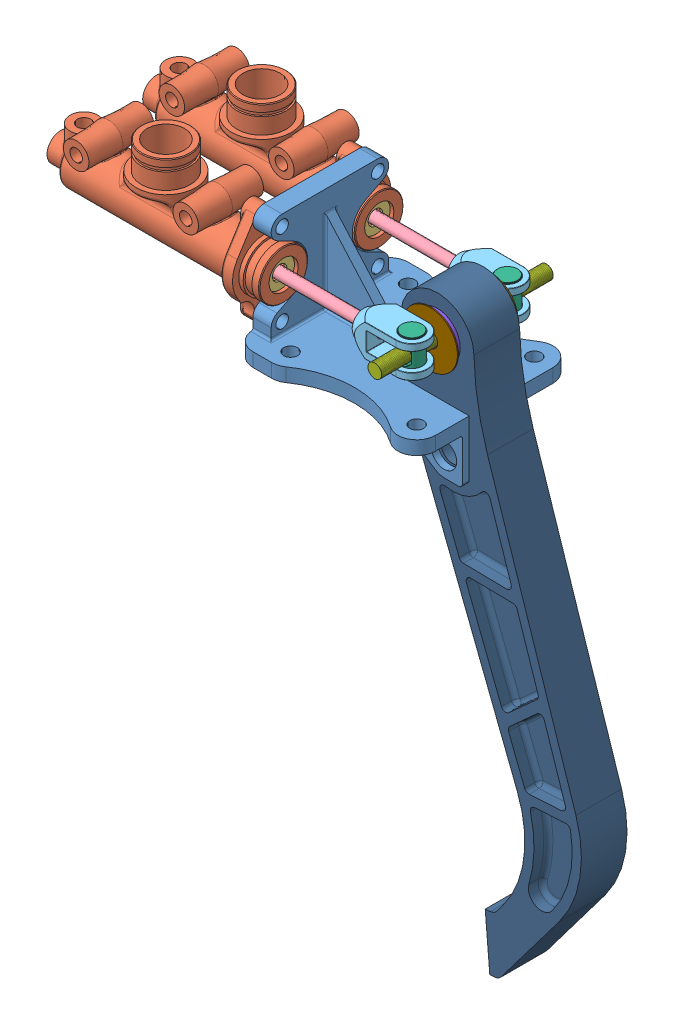
SolidWorks assembly pedalASM, configuration Default. Lengths in mm.
Overall size (389.96 409.12 121.21).
18 component instances, 10 part files, 27 mates.
Components (placement in the parent):
- PedalMastercylMount-1: PedalMastercylMount [Default] at (-61.6568 -16.4521 -5.96) size (127.05 113.66 107.95)
- mastercylinder asm-1: mastercylinder asm [Default] at (-69.6578 12.1229 27.314) x (0 0 -1) z (1 0 0) size (45.21 75.99 223.71)
  - mastercylinder-1: mastercylinder [Default] at origin size (45.21 75.99 154.88)
  - mastercylinder retaining washer-1: mastercylinder retaining washer [Default] at (0 0 17.145) size (20.83 20.83 1.91)
  - mastercylinder pushrod-1: mastercylinder pushrod [Default] at (0 0 90.551) x (-0.12806 0.991766 0) z (0 0 1) size (10.67 10.67 107.24)
- mastercylinder asm-2: mastercylinder asm [Default] at (-69.6578 12.1229 -39.234) x (0 0 -1) z (1 0 0) size (45.21 75.99 223.71)
  - mastercylinder-1: mastercylinder [Default] at origin size (45.21 75.99 154.88)
  - mastercylinder retaining washer-1: mastercylinder retaining washer [Default] at (0 0 17.145) size (20.83 20.83 1.91)
  - mastercylinder pushrod-1: mastercylinder pushrod [Default] at (0 0 90.551) x (-0.12806 0.991766 0) z (0 0 1) size (10.67 10.67 107.24)
- clevis-1: clevis [Default] at (41.4545 0.9469 27.5045) x (0 0 -1) z (1 0 0) size (21.97 22.28 44.25)
- clevis-2: clevis [Default] at (41.4545 0.9469 -39.0435) x (0 0 -1) z (1 0 0) size (21.97 22.28 44.25)
- clevis pin-3: clevis pin [Default] at (41.4545 0.2865 -39.0435) size (14.27 23.6 14.27)
- clevis pin-4: clevis pin [Default] at (41.4545 0.2865 27.5045) size (14.27 23.6 14.27)
- Balance bar-2: Balance bar [Default] at (41.5999 12.1359 -6.2775) x (-0.943579 -0.331147 0) z (-0.331147 0.943579 0) size (20.15 121.21 20.15)
- Bushing-1: Bushing [Default] at (41.6783 12.1634 14.2965) x (0 0 -1) z (0.852085 -0.523404 0) size (40.64 31.75 31.75)
- Washer-1: Washer [Default] at (41.6783 12.1634 15.0585) x (0 0 -1) z (0.988589 -0.150638 0) size (0.76 38.1 38.1)
- Washer-2: Washer [Default] at (41.6783 12.1634 -26.3435) x (0 0 -1) z (0.984471 -0.175545 0) size (0.76 38.1 38.1)
- brakepedaltest1-1: brakepedaltest1 [Default] at (52.6432 -51.3771 -5.96) x (0 0 1) z (-0.940935 -0.338587 0) size (31.75 384.44 115.48)
Mates (geometry in assembly coordinates):
- Coincident1: coincident anti-aligned: plane of PedalMastercylMount-1 through (-61.6568 12.1229 27.314) normal (-1 0 0); plane of mastercylinder asm-1/mastercylinder-1 through (-61.6568 40.6979 27.314) normal (1 0 0)
- Concentric1: concentric aligned: cylinder of PedalMastercylMount-1 through (-48.9568 40.6979 27.314) axis (-1 0 0) radius 4.3656; cylinder of mastercylinder asm-1/mastercylinder-1 through (-61.6568 40.6979 27.314) axis (-1 0 0) radius 4.3656
- Concentric2: concentric aligned: cylinder of PedalMastercylMount-1 through (-48.9568 -16.4521 27.314) axis (-1 0 0) radius 4.3656; cylinder of mastercylinder asm-1/mastercylinder-1 through (-61.6568 -16.4521 27.314) axis (-1 0 0) radius 4.3656
- Coincident2: coincident anti-aligned: plane of PedalMastercylMount-1 through (-61.6568 12.1229 27.314) normal (-1 0 0); plane of mastercylinder asm-2/mastercylinder-1 through (-61.6568 40.6979 -39.234) normal (1 0 0)
- Concentric3: concentric aligned: cylinder of PedalMastercylMount-1 through (-48.9568 40.6979 -39.234) axis (-1 0 0) radius 4.3656; cylinder of mastercylinder asm-2/mastercylinder-1 through (-61.6568 40.6979 -39.234) axis (-1 0 0) radius 4.3656
- Concentric4: concentric aligned: cylinder of PedalMastercylMount-1 through (-48.9568 -16.4521 -39.234) axis (-1 0 0) radius 4.3656; cylinder of mastercylinder asm-2/mastercylinder-1 through (-61.6568 -16.4521 -39.234) axis (-1 0 0) radius 4.3656
- Concentric8: concentric anti-aligned: cylinder of mastercylinder asm-1/mastercylinder pushrod-1 through (20.8932 12.1229 27.314) axis (1 0 0) radius 3.81; circle of clevis-1
- Concentric13: concentric anti-aligned: cylinder of mastercylinder asm-2/mastercylinder pushrod-1 through (20.8932 12.1229 -39.234) axis (1 0 0) radius 3.81; circle of clevis-2
- Coincident4: coincident aligned: plane of mastercylinder asm-2/mastercylinder pushrod-1 through (20.8932 12.1229 -39.234) normal (1 0 0); plane of clevis-2 through (20.8932 18.4348 -26.3435) normal (1 0 0)
- Coincident5: coincident aligned: plane of mastercylinder asm-1/mastercylinder pushrod-1 through (20.8932 12.1229 27.314) normal (1 0 0); plane of clevis-1 through (20.8932 18.4348 40.2045) normal (1 0 0)
- Coincident6: coincident aligned: plane of clevis-1 through (41.4545 23.2227 27.5045) normal (0 1 0); plane of clevis-2 through (41.4545 23.2227 -39.0435) normal (0 1 0)
- Concentric14: concentric anti-aligned: cylinder of clevis pin-4 through (41.4545 12.0848 20.329) axis (0 0 1) radius 4.7625; circle of Balance bar-2
- Concentric15: concentric aligned: circle of clevis pin-3; circle of Balance bar-2
- Concentric16: concentric aligned: cylinder of clevis-1 through (41.4545 23.2227 27.5045) axis (0 -1 0) radius 7.239; cylinder of clevis pin-4 through (41.4545 23.8831 27.5045) axis (0 -1 0) radius 7.1374
- Tangent5: tangent anti-aligned: plane of clevis-1 through (52.44 5.7348 40.2045) normal (0 1 0); cylinder of clevis pin-4 through (41.4545 12.0848 20.3671) axis (0 0 1) radius 6.35
- Concentric17: concentric aligned: cylinder of clevis-2 through (41.4545 23.2227 -39.0435) axis (0 -1 0) radius 7.239; cylinder of clevis pin-3 through (41.4545 23.8831 -39.0435) axis (0 -1 0) radius 7.1374
- Tangent6: tangent anti-aligned: plane of clevis-2 through (52.44 5.7348 -26.3435) normal (0 1 0); cylinder of clevis pin-3 through (41.4545 12.0848 -46.1809) axis (0 0 1) radius 6.35
- Concentric18: concentric anti-aligned: circle of Balance bar-2; cylinder of Bushing-1 through (41.6783 12.1634 -26.3435) axis (0 0 1) radius 12.7
- Distance1: distance = 18.796 mm anti-aligned: plane of Balance bar-2 through (41.5999 12.1359 -15.1675) normal (0 0 -1); plane of clevis pin-3 through (41.4545 12.0848 -33.9635) normal (0 0 1)
- Distance2: distance = 11.176 mm aligned: plane of Balance bar-2 through (41.5999 12.1359 -15.1675) normal (0 0 -1); plane of Bushing-1 through (41.6783 12.1634 -26.3435) normal (0 0 -1)
- Concentric19: concentric anti-aligned: cylinder of Bushing-1 through (41.6783 12.1634 -26.3435) axis (0 0 1) radius 15.875; circle of Washer-1
- Coincident14: coincident anti-aligned: plane of Bushing-1 through (41.6783 12.1634 14.2965) normal (0 0 1); plane of Washer-1 through (41.6783 12.1634 14.2965) normal (0 0 -1)
- Concentric20: concentric anti-aligned: cylinder of Bushing-1 through (41.6783 12.1634 -26.3435) axis (0 0 1) radius 15.875; circle of Washer-2
- Coincident15: coincident anti-aligned: plane of Bushing-1 through (41.6783 12.1634 -26.3435) normal (0 0 -1); plane of Washer-2 through (41.6783 12.1634 -26.3435) normal (0 0 1)
- Concentric21: concentric anti-aligned: cylinder of Bushing-1 through (41.6783 12.1634 -26.3435) axis (0 0 1) radius 15.875; cylinder of brakepedaltest1-1 through (41.6783 12.1634 9.915) axis (0 0 -1) radius 15.875
- Distance3: distance = 1.5875 mm anti-aligned: plane of brakepedaltest1-1 through (52.6432 -51.3771 -21.835) normal (0 0 -1); plane of PedalMastercylMount-1 through (65.3432 -33.5971 -23.4225) normal (0 0 1)
- Concentric22: concentric aligned: circle of PedalMastercylMount-1; cylinder of brakepedaltest1-1 through (52.6432 -51.3771 9.915) axis (0 0 -1) radius 8.8004
